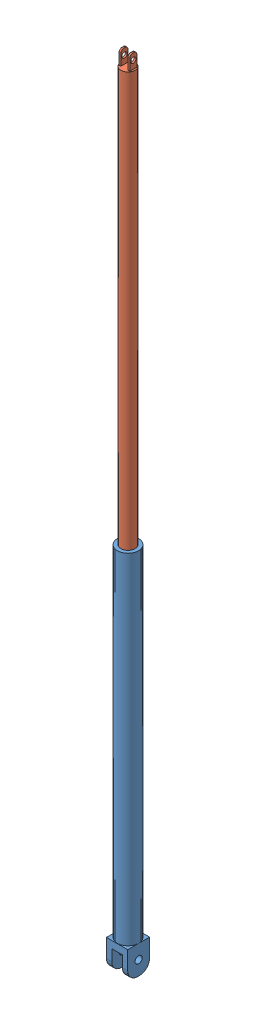
SolidWorks assembly CrowsNest LinActuator, configuration Default. Lengths in mm.
Overall size (76.2 2857.16 78.39).
2 component instances, 2 part files, 2 mates.
Components (placement in the parent):
- Stanchion Outer-1: Stanchion Outer [Default] at origin size (76.2 1320.8 78.39)
- Stanchion Inner-1: Stanchion Inner [Default] at (0 1180.7593 0) size (50.8 1574.8 50.8)
Mates (geometry in assembly coordinates):
- Concentric1: concentric aligned: cylinder of Stanchion Outer-1 through (0 1219.2 0) axis (0 -1 0) radius 38.1; cylinder of Stanchion Inner-1 through (0 2704.7593 0) axis (0 -1 0) radius 25.4
- Coincident1: coincident aligned: plane of Stanchion Outer-1 through (0 0 0) normal (0 0 1); plane of Stanchion Inner-1 through (0 1180.7593 0) normal (0 0 1)
